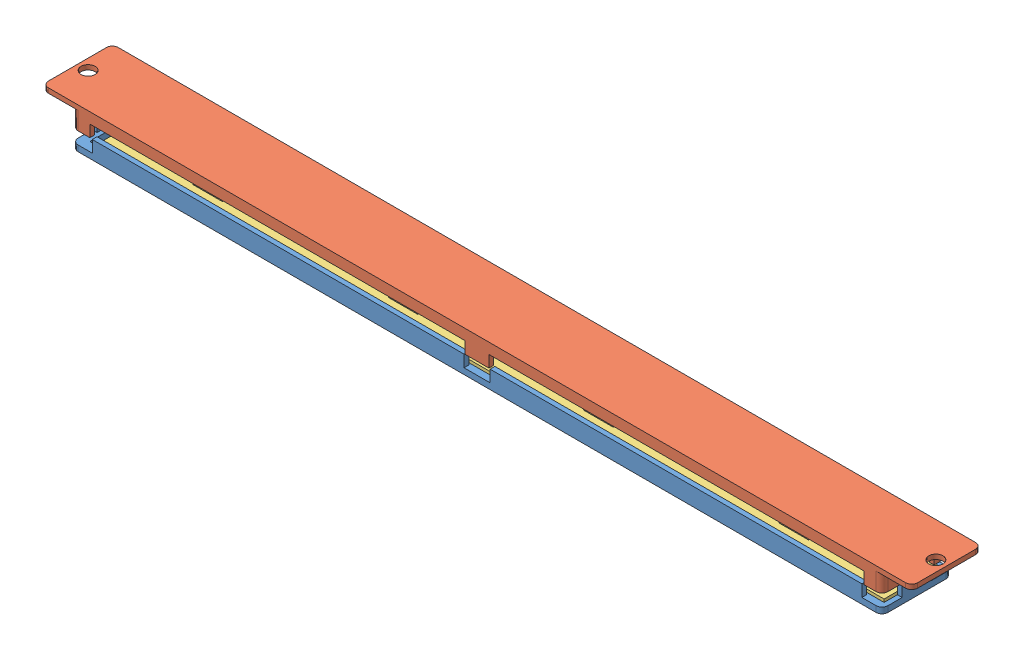
SolidWorks assembly Assemblage_Led, configuration Défaut. Lengths in mm.
Overall size (146.8 6.85 11.8).
3 component instances, 3 part files, 6 mates.
Components (placement in the parent):
- Boitier_led_pc1-1: Boitier_led_pc1 [Défaut] at (-81.0469 1.7855 138) size (136.8 3 11.8)
- Boitier_led_pc2-1: Boitier_led_pc2 [Défaut] at (55.7531 8.6372 138) x (-1 0 0) z (0 0 1) size (146.8 3.8 11.8)
- Rubant_4leds-1: Rubant_4leds [Défaut] at (-78.0469 2.7855 136.85) size (133 2.5 9.5)
Mates (geometry in assembly coordinates):
- Coïncidente1: coincident anti-aligned: plane of Boitier_led_pc1-1 through (-81.0469 2.7855 138) normal (0 1 0); plane of Rubant_4leds-1 through (-78.0469 2.7855 136.85) normal (0 -1 0)
- Distance1: distance = 0.35 mm anti-aligned: plane of Rubant_4leds-1 through (-78.0469 3.2855 127.35) normal (0 0 -1); plane of Boitier_led_pc1-1 through (54.9531 4.7855 127) normal (0 0 1)
- Coïncidente3: coincident anti-aligned: plane of Boitier_led_pc1-1 through (54.9531 4.7855 127) normal (-1 0 0); plane of Rubant_4leds-1 through (54.9531 3.2855 136.85) normal (1 0 0)
- Coïncidente5: coincident aligned: plane of Boitier_led_pc1-1 through (-81.0469 2.7855 138) normal (-1 0 0); plane of Boitier_led_pc2-1 through (-81.0469 7.8372 138) normal (-1 0 0)
- Coïncidente6: coincident aligned: plane of Boitier_led_pc1-1 through (-81.0469 2.7855 138) normal (0 0 1); plane of Boitier_led_pc2-1 through (55.7531 7.8372 138) normal (0 0 1)
- DistanceLimite1: limit distance = 2.0517 mm anti-aligned: plane of Boitier_led_pc2-1 through (55.7531 4.8372 138) normal (0 -1 0); plane of Boitier_led_pc1-1 through (-81.0469 2.7855 138) normal (0 1 0)
